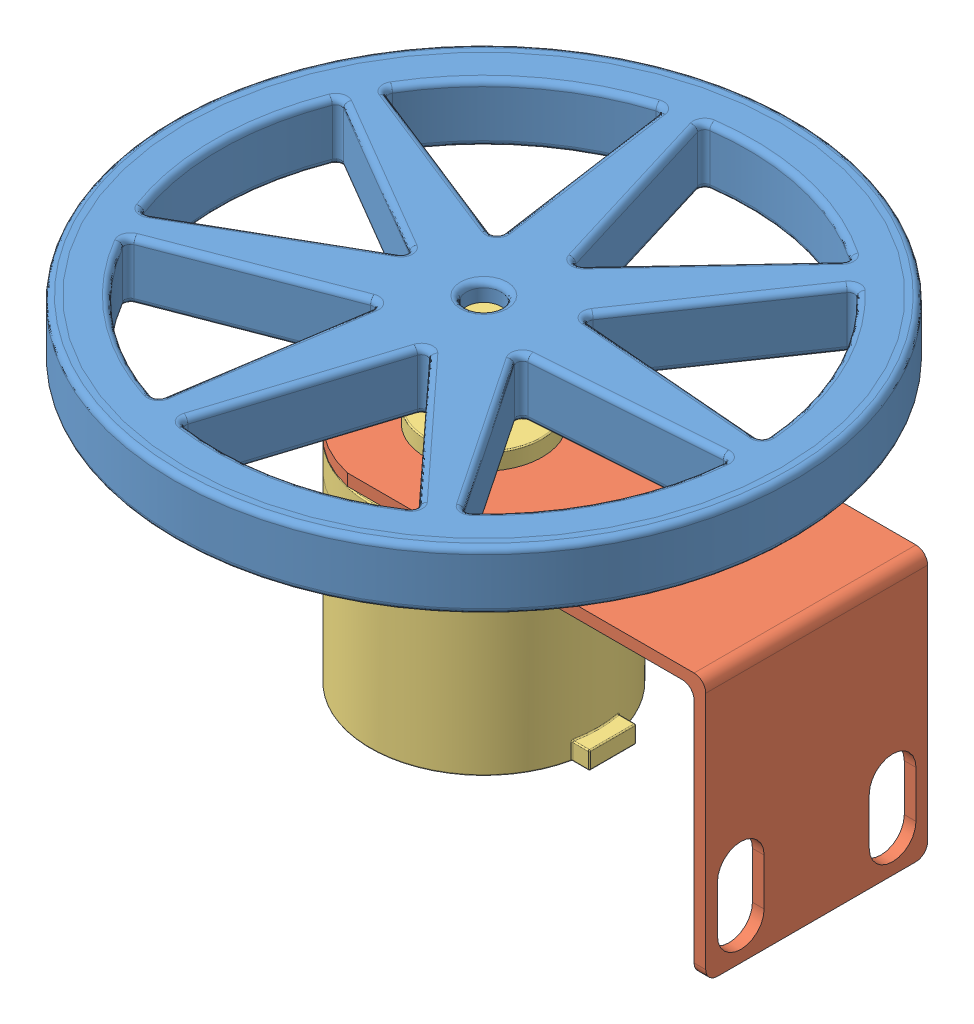
SolidWorks assembly Leg_Assembly_Mirror, configuration Default. Lengths in mm.
Overall size (110 64 106).
3 component instances, 3 part files, 5 mates.
Components (placement in the parent):
- 106_alum_wheel-1: 106_alum_wheel [Default] at (35.9984 80.6835 65.9188) size (106 18 106)
- encoder_bracket-1: encoder_bracket [Default] at (31.6109 71.6835 46.9188) x (1 0 0) z (0 0 -1) size (76.5 45 38)
- encoder-1: encoder [Default] at (35.9984 33.1835 65.9188) x (0 0 -1) z (1 0 0) size (39 54.35 41.59)
Mates (geometry in assembly coordinates):
- Concentric1: concentric anti-aligned: cylinder of encoder_bracket-1 through (35.9984 69.6835 65.9188) axis (0 1 0) radius 10; cylinder of encoder-1 through (35.9984 74.5335 65.9188) axis (0 -1 0) radius 10
- Coincident1: coincident anti-aligned: plane of encoder_bracket-1 through (31.6109 69.6835 46.9188) normal (0 -1 0); plane of encoder-1 through (35.9984 69.6835 65.9188) normal (0 1 0)
- Concentric2: concentric anti-aligned: circle of 106_alum_wheel-1; cylinder of encoder-1 through (35.9984 87.5335 65.9188) axis (0 -1 0) radius 3
- Distance1: distance = 1 mm anti-aligned: plane of encoder_bracket-1 through (31.6109 71.6835 46.9188) normal (0 1 0); plane of 106_alum_wheel-1 through (35.9984 72.6835 65.9188) normal (0 -1 0)
- Parallel1: parallel anti-aligned: plane of encoder_bracket-1 through (90.9984 26.6835 46.9188) normal (-1 0 0); plane of encoder-1 through (58.0838 36.1835 69.9188) normal (1 0 0)
